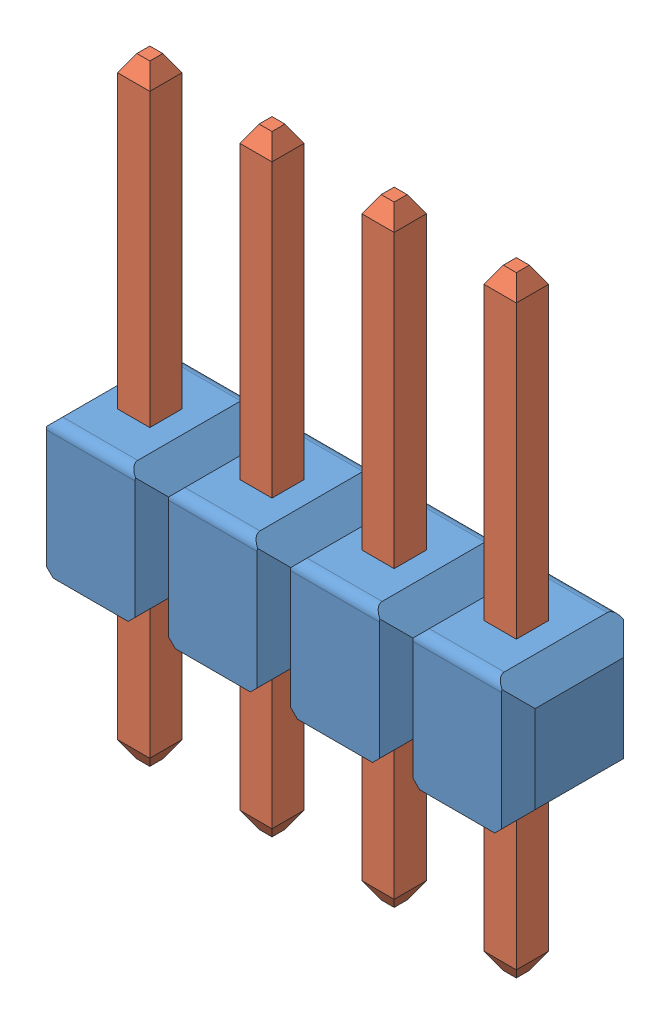
SolidWorks assembly User Library-1x4 TH Pitch 2_54mm, configuration Default. Lengths in mm.
Overall size (10.16 12.7 2.54).
5 component instances, 2 part files, 0 mates.
Components (placement in the parent):
- User Library-1x4 TH Pitch 2_54mm_holder-1: User Library-1x4 TH Pitch 2_54mm_holder [Default] at (0 1.4 0) size (10.16 2.8 2.54)
- User Library-1x4 TH Pitch 2_54mm_pin-1: User Library-1x4 TH Pitch 2_54mm_pin [Default] at (-3.83 -3.5 0.02) size (0.67 12.7 0.67)
- User Library-1x4 TH Pitch 2_54mm_pin-2: User Library-1x4 TH Pitch 2_54mm_pin [Default] at (-1.29 -3.5 0.02) size (0.67 12.7 0.67)
- User Library-1x4 TH Pitch 2_54mm_pin-3: User Library-1x4 TH Pitch 2_54mm_pin [Default] at (1.25 -3.5 0.02) size (0.67 12.7 0.67)
- User Library-1x4 TH Pitch 2_54mm_pin-4: User Library-1x4 TH Pitch 2_54mm_pin [Default] at (3.79 -3.5 0.02) size (0.67 12.7 0.67)
